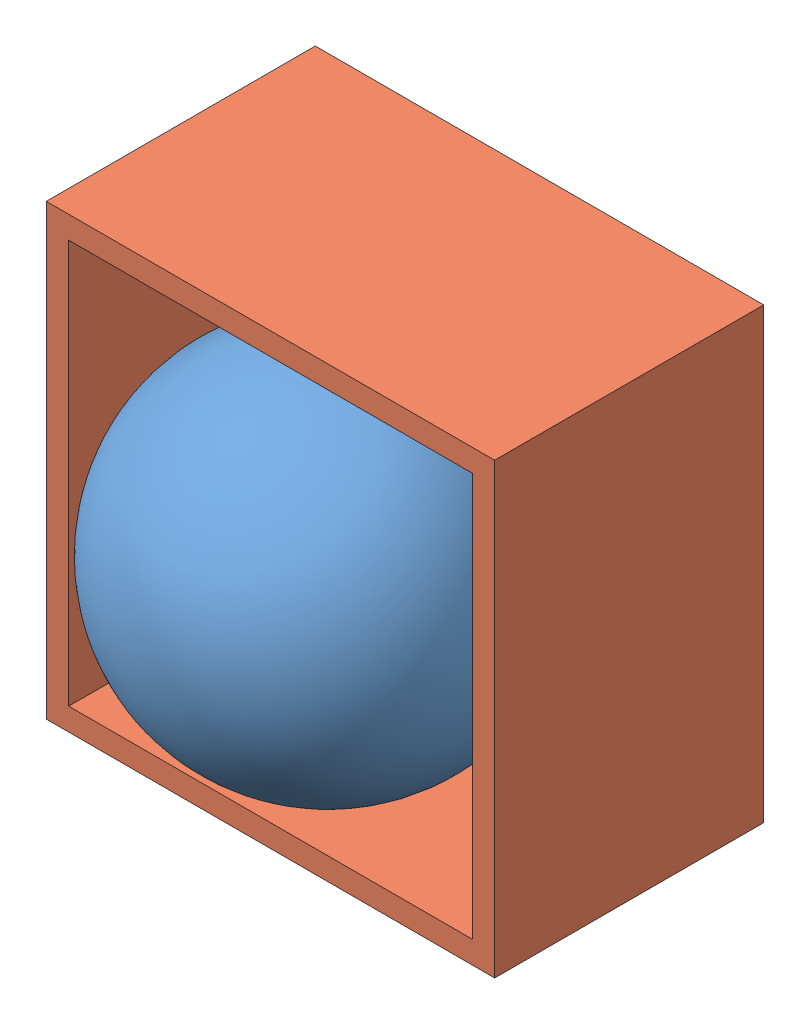
SolidWorks assembly BearingContainerAsm, configuration Default. Lengths in mm.
Overall size (50 50 43.6).
2 component instances, 2 part files, 0 mates.
Components (placement in the parent):
- miniball-2: miniball [Default] at (64.8074 29.1677 66.8602) size (40 40 40)
- container-3: container [Default] at (97.5898 25.7275 23.2563) x (-1 0 0) z (0 0 -1) size (50 50 30)
